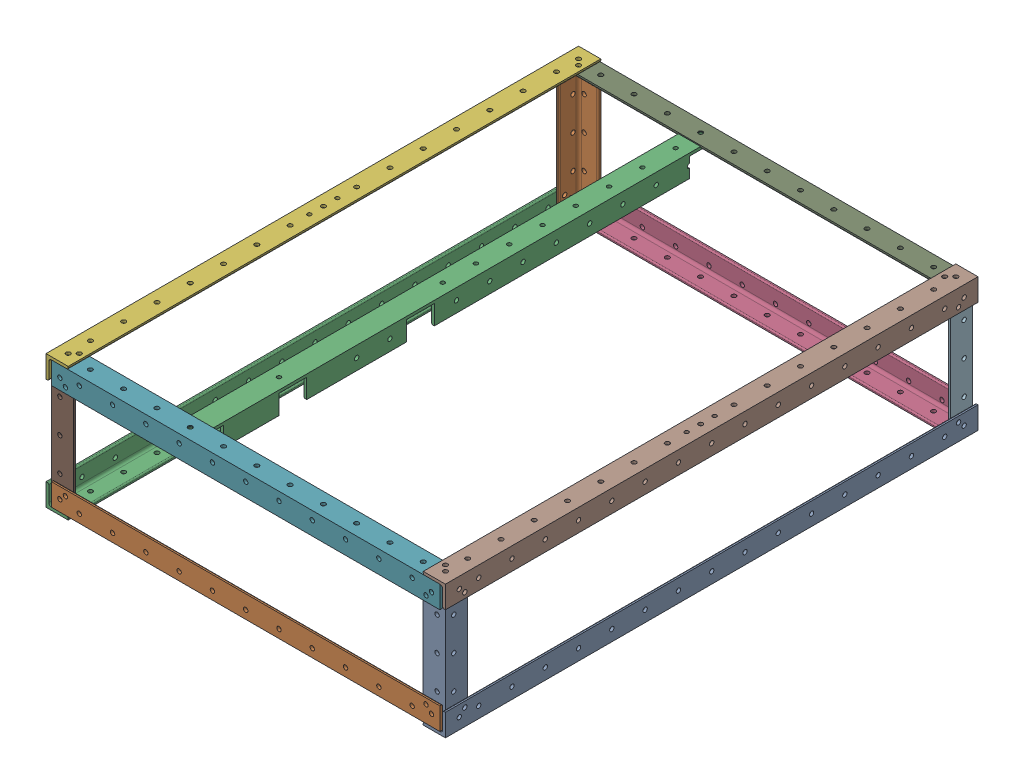
SolidWorks assembly Frame Chassis, configuration Default. Lengths in mm.
Overall size (457.2 152.4 609.6).
17 component instances, 5 part files, 16 mates.
Components (placement in the parent):
- Horizontal Assembly-1: Horizontal Assembly [Default] at origin size (457.2 28.57 609.6)
  - Long-Side Horizontal L-Bar-1: Long-Side Horizontal L-Bar [8982K402] at origin size (25.4 25.4 609.6)
  - Short-Side Horizontal L-Bar-1: Short-Side Horizontal L-Bar [8982K402] at (-298.45 3.175 292.1) x (0 0 1) z (-1 0 0) size (25.4 25.4 444.5)
  - Long-Side Horizontal L-Bar-2: Long-Side Horizontal L-Bar [8982K402] at (-431.8 0 0) x (-1 0 0) z (0 0 -1) size (25.4 25.4 609.6)
  - Short-Side Horizontal L-Bar-2: Short-Side Horizontal L-Bar [8982K402] at (-133.35 3.175 -292.1) x (0 0 -1) z (1 0 0) size (25.4 25.4 444.5)
  - Nut Holder-1: Nut Holder [Default] at (-4.7625 15.875 287.3375) x (-1 0 0) z (0 -1 0) size (22.23 22.23 22.23)
- Horizontal Assembly-2: Horizontal Assembly [Default] at (-431.8 127 0) x (-1 0 0) z (0 0 1) size (457.2 28.57 609.6)
  - Long-Side Horizontal L-Bar-1: Long-Side Horizontal L-Bar [8982K402] at origin size (25.4 25.4 609.6)
  - Short-Side Horizontal L-Bar-1: Short-Side Horizontal L-Bar [8982K402] at (-298.45 3.175 292.1) x (0 0 1) z (-1 0 0) size (25.4 25.4 444.5)
  - Long-Side Horizontal L-Bar-2: Long-Side Horizontal L-Bar [8982K402] at (-431.8 0 0) x (-1 0 0) z (0 0 -1) size (25.4 25.4 609.6)
  - Short-Side Horizontal L-Bar-2: Short-Side Horizontal L-Bar [8982K402] at (-133.35 3.175 -292.1) x (0 0 -1) z (1 0 0) size (25.4 25.4 444.5)
  - Nut Holder-1: Nut Holder [Default] at (-4.7625 15.875 287.3375) x (-1 0 0) z (0 -1 0) size (22.23 22.23 22.23)
- Vertical L-Bar-1: Vertical L-Bar [8982K402] at (-428.625 301.625 288.925) x (0 0 1) z (0 1 0) size (25.4 25.4 133.35)
- Vertical L-Bar-2: Vertical L-Bar [8982K402] at (-3.175 301.625 -288.925) x (0 0 -1) z (0 1 0) size (25.4 25.4 133.35)
- Vertical L-Bar-3: Vertical L-Bar [8982K402] at (-3.175 -174.625 288.925) x (0 0 1) z (0 -1 0) size (25.4 25.4 133.35)
- Vertical L-Bar-4: Vertical L-Bar [8982K402] at (-428.625 -174.625 -288.925) x (0 0 -1) z (0 -1 0) size (25.4 25.4 133.35)
- Slotted Box L-Bar-1: Slotted Box L-Bar [8982K402] at (-292.1 122.638 6.35) x (0 1 0) z (0 0 1) size (25.4 25.4 596.9)
Mates (geometry in assembly coordinates):
- Coincident1: coincident anti-aligned: plane of Horizontal Assembly-1/Long-Side Horizontal L-Bar-2 through (-441.325 11.1125 -304.8) normal (1 0 0); plane of Vertical L-Bar-1 through (-441.325 606.425 276.225) normal (-1 0 0)
- Concentric1: concentric aligned: circle of Horizontal Assembly-1/Long-Side Horizontal L-Bar-2; circle of Vertical L-Bar-1
- Concentric3: concentric anti-aligned: cylinder of Horizontal Assembly-2/Long-Side Horizontal L-Bar-1 through (-190.5 127 288.925) axis (-1 0 0) radius 2.5; circle of Vertical L-Bar-1
- Concentric4: concentric aligned: cylinder of Horizontal Assembly-2/Short-Side Horizontal L-Bar-1 through (-428.625 123.825 50.8) axis (0 0 1) radius 2.5; cylinder of Vertical L-Bar-1 through (-428.625 123.825 47.625) axis (0 0 1) radius 2.5
- Concentric6: concentric anti-aligned: cylinder of Horizontal Assembly-2/Long-Side Horizontal L-Bar-1 through (-190.5 127 -288.925) axis (-1 0 0) radius 2.5; circle of Vertical L-Bar-4
- Concentric7: concentric aligned: circle of Horizontal Assembly-2/Long-Side Horizontal L-Bar-1; cylinder of Vertical L-Bar-4 through (-682.625 120.65 -282.575) axis (1 0 0) radius 2.5
- Concentric8: concentric aligned: circle of Horizontal Assembly-2/Short-Side Horizontal L-Bar-2; circle of Vertical L-Bar-4
- Concentric9: concentric aligned: circle of Horizontal Assembly-1/Long-Side Horizontal L-Bar-2; circle of Vertical L-Bar-4
- Concentric13: concentric aligned: circle of Horizontal Assembly-2/Long-Side Horizontal L-Bar-2; cylinder of Vertical L-Bar-3 through (250.825 127 288.925) axis (-1 0 0) radius 2.5
- Concentric14: concentric anti-aligned: cylinder of Horizontal Assembly-2/Long-Side Horizontal L-Bar-2 through (-241.3 120.65 282.575) axis (1 0 0) radius 2.5; cylinder of Vertical L-Bar-3 through (250.825 120.65 282.575) axis (-1 0 0) radius 2.5
- Concentric15: concentric anti-aligned: cylinder of Horizontal Assembly-2/Short-Side Horizontal L-Bar-1 through (-3.175 123.825 50.8) axis (0 0 1) radius 2.5; circle of Vertical L-Bar-3
- Concentric16: concentric aligned: circle of Horizontal Assembly-2/Short-Side Horizontal L-Bar-2; circle of Vertical L-Bar-2
- Concentric17: concentric aligned: circle of Horizontal Assembly-2/Long-Side Horizontal L-Bar-2; circle of Vertical L-Bar-2
- Concentric18: concentric aligned: cylinder of Horizontal Assembly-2/Short-Side Horizontal L-Bar-2 through (-9.525 117.475 -50.8) axis (0 0 -1) radius 2.5; cylinder of Vertical L-Bar-2 through (-9.525 117.475 -47.625) axis (0 0 -1) radius 2.5
- Concentric19: concentric: circle of Horizontal Assembly-2/Short-Side Horizontal L-Bar-2; circle of Slotted Box L-Bar-1
- Concentric20: concentric anti-aligned: cylinder of Horizontal Assembly-2/Short-Side Horizontal L-Bar-1 through (-292.1 377.825 292.1) axis (0 -1 0) radius 2.5; cylinder of Slotted Box L-Bar-1 through (-292.1 -118.662 292.1) axis (0 1 0) radius 2.25
